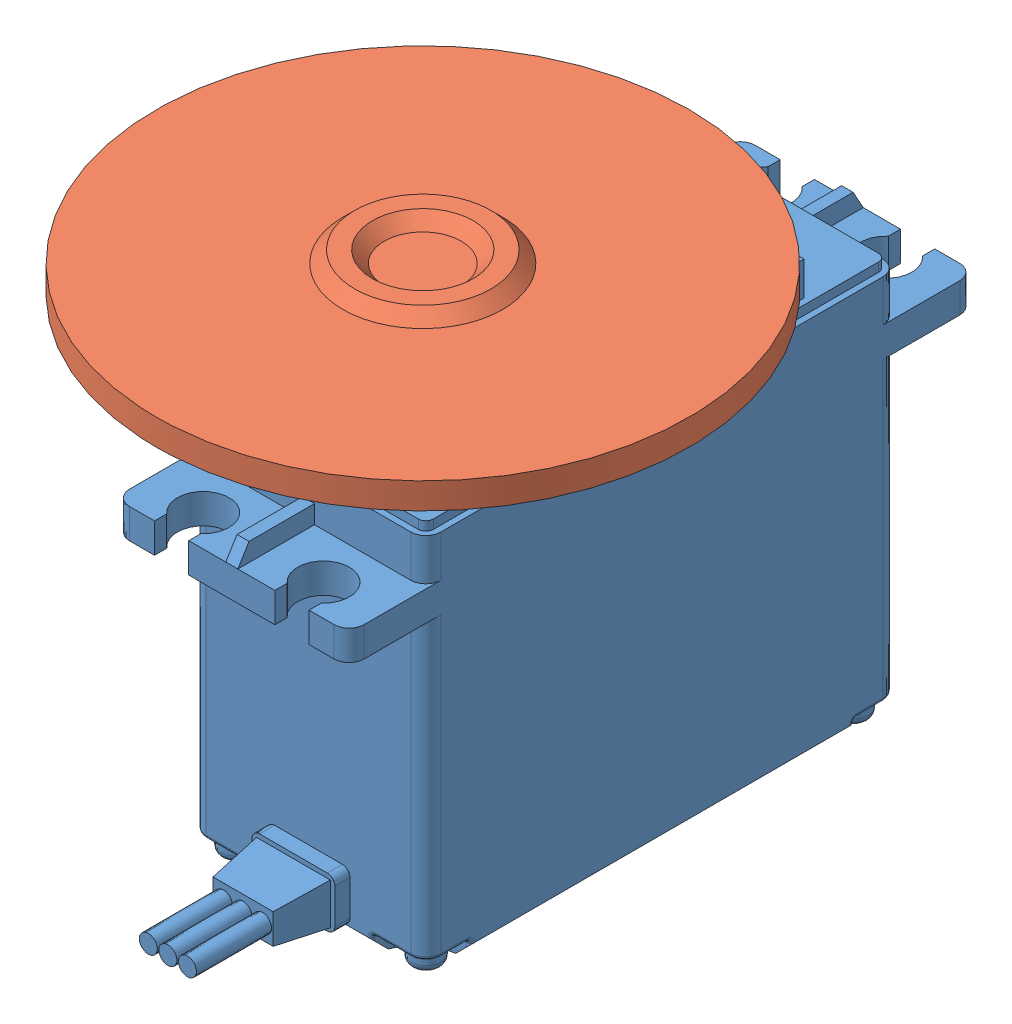
SolidWorks assembly conjuntoServo, configuration Default. Lengths in mm.
Overall size (45 44.26 59.2).
2 component instances, 2 part files, 2 mates.
Components (placement in the parent):
- hs-422_sws-1: hs-422_sws [Default] at (-9.4092 -1.9341 -1.8657) size (19.81 42.14 58.23)
- discoServo-1: discoServo [Default] at (0.4968 18.3821 8.4213) size (45 3.2 45)
Mates (geometry in assembly coordinates):
- Concentric1: concentric: circle of hs-422_sws-1; circle of discoServo-1
- Distance1: distance = 5 mm anti-aligned: plane of discoServo-1 through (0.4968 18.3821 8.4213) normal (0 -1 0); plane of hs-422_sws-1 through (10.4028 13.3821 -1.8657) normal (0 1 0)
